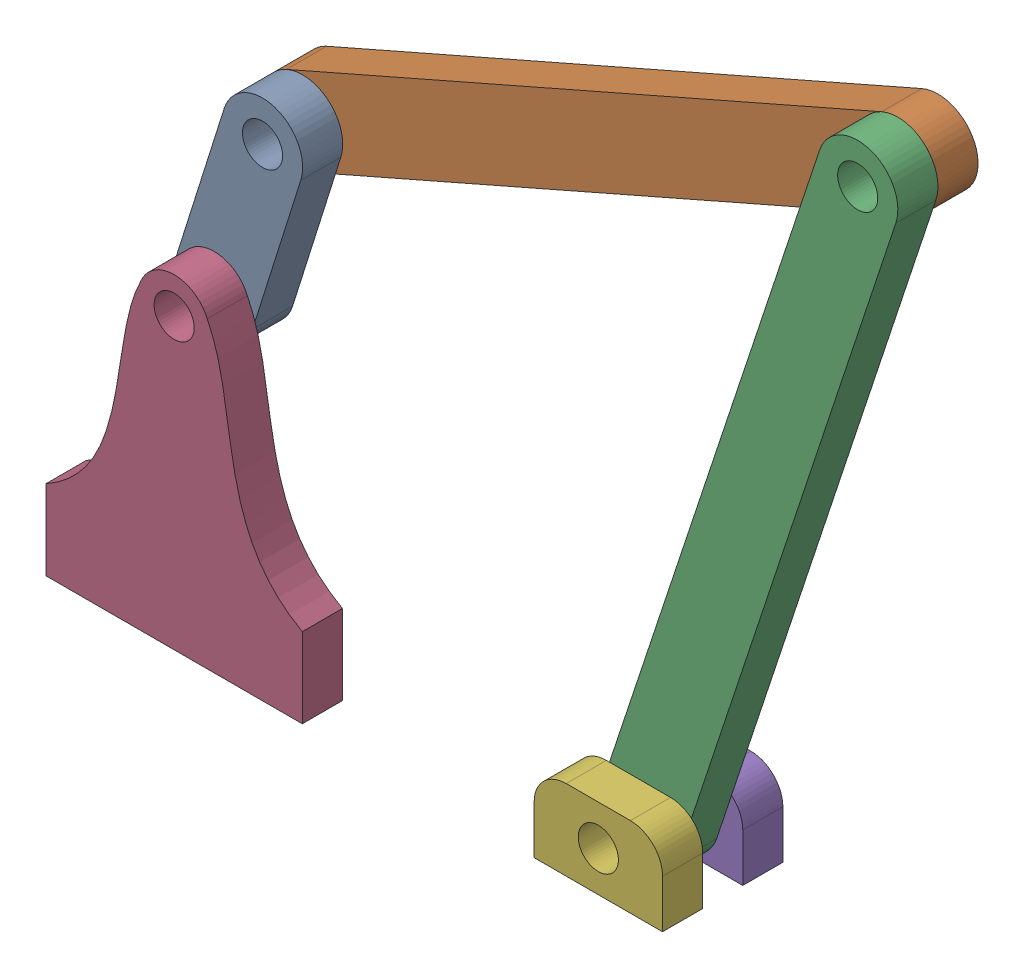
SolidWorks assembly linkage_assem, configuration Default. Lengths in mm.
Overall size (130.5 121.29 19.05).
6 component instances, 5 part files, 15 mates.
Components (placement in the parent):
- link1-1: link1 [Default] at (6.1404 45.72 -12.7) x (0.953746 -0.300613 0) z (0 0 1) size (12.7 38.1 6.35)
- link2-1: link2 [Default] at (13.776 69.9452 -19.05) x (0.401507 -0.915856 0) z (0 0 1) size (12.7 115.57 6.35)
- link3-1: link3 [Default] at (73.2853 6.35 -12.7) x (0.94939 -0.314099 0) z (0 0 1) size (12.7 123.19 6.35)
- stand-1: stand [Default] at (6.1404 0 -6.35) size (40.57 51.44 6.35)
- small_stand-1: small_stand [Default] at (63.1253 0 -19.05) size (20.32 12.7 6.35)
- small_stand-2: small_stand [Default] at (63.1253 0 -6.35) size (20.32 12.7 6.35)
Mates (geometry in assembly coordinates):
- Coincident1: coincident anti-aligned: plane of link1-1 through (13.776 69.9452 -12.7) normal (0 0 -1); plane of link2-1 through (107.9901 111.2481 -12.7) normal (0 0 1)
- Concentric1: concentric aligned: circle of link1-1; circle of link2-1
- Concentric2: concentric aligned: cylinder of link2-1 through (107.9901 111.2481 -12.7) axis (0 0 -1) radius 3.175; cylinder of link3-1 through (107.9901 111.2481 -6.35) axis (0 0 -1) radius 3.175
- Coincident4: coincident anti-aligned: plane of link2-1 through (107.9901 111.2481 -12.7) normal (0 0 1); plane of link3-1 through (107.9901 111.2481 -12.7) normal (0 0 -1)
- Coincident12: coincident anti-aligned: plane of link1-1 through (13.776 69.9452 -6.35) normal (0 0 1); plane of stand-1 through (-3.5333 28.6354 -6.35) normal (0 0 -1)
- Coincident13: coincident anti-aligned: cylinder of link1-1 through (6.1404 45.72 -6.35) axis (0 0 -1) radius 3.175; circle of stand-1
- Tangent1: tangent anti-aligned: cylinder of link3-1 through (73.2853 6.35 -6.35) axis (0 0 -1) radius 6.35
- Coincident18: coincident anti-aligned: plane of link3-1 through (107.9901 111.2481 -6.35) normal (0 0 1); plane of small_stand-2 through (68.2053 7.62 -6.35) normal (0 0 -1)
- Concentric8: concentric aligned: circle of link3-1; circle of small_stand-2
- Coincident23: coincident aligned: plane of small_stand-1 through (63.1253 0 -12.7) normal (0 -1 0); plane of small_stand-2 through (63.1253 0 0) normal (0 -1 0)
- Coincident37: coincident anti-aligned: plane of link3-1 through (107.9901 111.2481 -12.7) normal (0 0 -1); plane of small_stand-1 through (68.2053 7.62 -12.7) normal (0 0 1)
- Concentric14: concentric aligned: circle of link3-1; circle of small_stand-1
- Distance2: distance = 36.7 mm anti-aligned: plane of stand-1 through (26.4253 0 0) normal (1 0 0); plane of small_stand-2 through (63.1253 0 0) normal (-1 0 0)
- Coincident41: coincident aligned: plane of small_stand-1 through (63.1253 0 -12.7) normal (0 -1 0); plane of stand-1 through (26.4253 0 0) normal (0 -1 0)
- Coincident42: coincident aligned: plane of stand-1 through (-3.5333 28.6354 0) normal (0 0 1); plane of small_stand-2 through (68.2053 7.62 0) normal (0 0 1)
